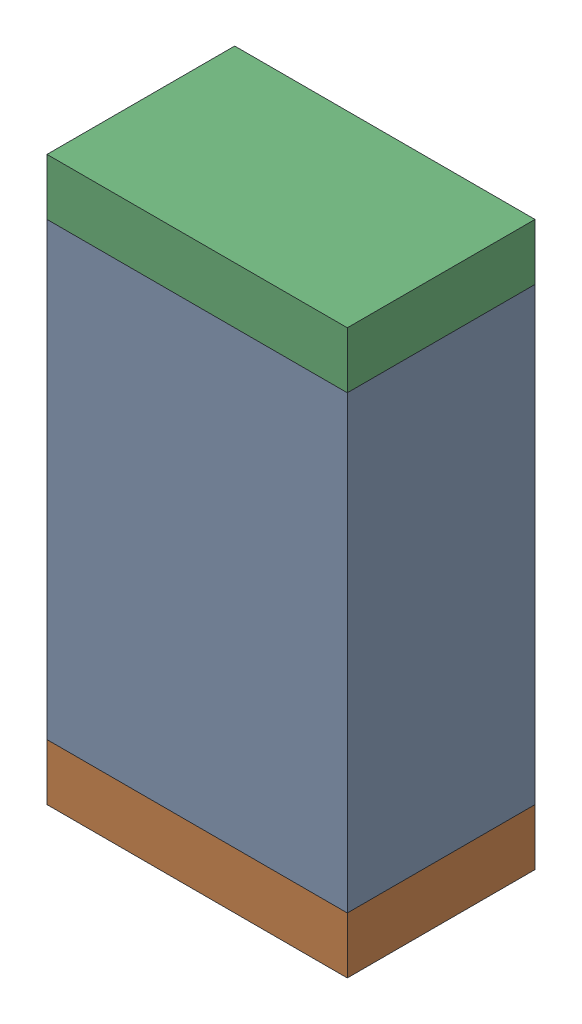
SolidWorks assembly C40, configuration Default. Lengths in mm.
Overall size (0.8 1.5 0.5).
6 component instances, 2 part files, 0 mates.
Components (placement in the parent):
- 810156976-1: 810156976 [Default] at (127.25 35.65 0) size (0.8 1.2 0.5)
  - Extruded_6-1: Extruded_6 [Default] at origin size (0.8 1.2 0.5)
- 810156592-1: 810156592 [Default] at (127.25 34.975 0) size (0.8 0.15 0.5)
  - Extruded_7-1: Extruded_7 [Default] at origin size (0.8 0.15 0.5)
- 810156592-2: 810156592 [Default] at (127.25 36.325 0) size (0.8 0.15 0.5)
  - Extruded_7-1: Extruded_7 [Default] at origin size (0.8 0.15 0.5)
